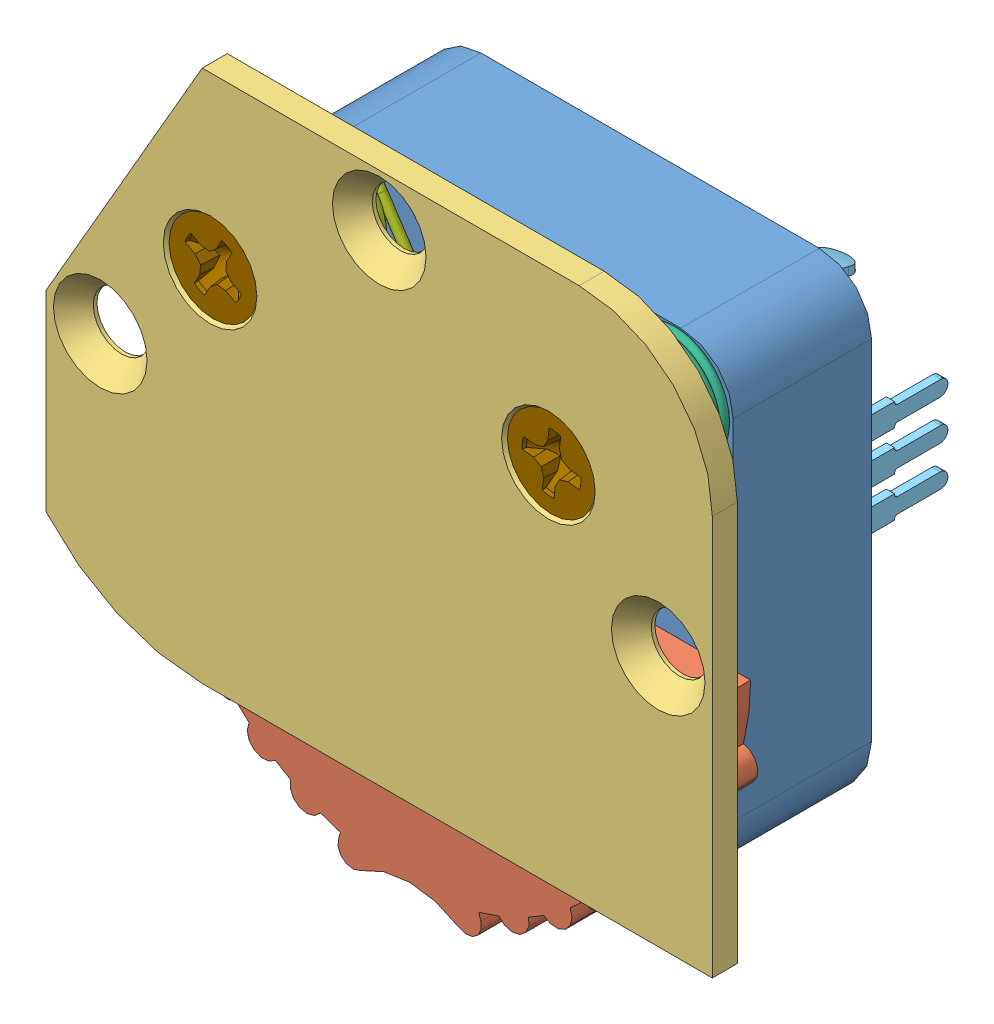
SolidWorks assembly ANT ELEV Switch, configuration Default. Lengths in mm.
Overall size (40.64 39.57 28.62).
13 component instances, 9 part files, 25 mates.
Components (placement in the parent):
- ANT ELEV Mechanism Bracket-1: ANT ELEV Mechanism Bracket [Default] at origin size (27.01 28.27 15)
- ANT ELEV Wheel-1: ANT ELEV Wheel [Default] at (0 0 9.398) x (-1 0 0) z (0 0 -1) size (30.3 23.15 6.22)
- ANT ELEV Mounting Plate-1: ANT ELEV Mounting Plate [Default] at (20.32 -8.9535 9.7282) x (0 1 0) z (0 0 1) size (32.51 40.64 1.52)
- ANT ELEV Pot Clamp-1: ANT ELEV Pot Clamp [Default] at (0 0 -5.2718) x (-1 0 0) z (0 0 -1) size (17.28 9.5 8.47)
- EVU-F2MFK3B14 - Pot, 10k Linear, PTH, M9 x 0.75 bushing, No Switch-1: EVU-F2MFK3B14 - Pot, 10k Linear, PTH, M9 x 0.75 bushing, No Switch [Default] at (0 0 -5.2718) x (0 1 0) z (0 0 1) size (10.82 13.51 27.1)
- 9271K632 - SPRING, TORSION, 360 DEG, LH WOUND, .187 SHAFT x 1.000 LEG, STEEL-1: 9271K632 - SPRING, TORSION, 360 DEG, LH WOUND, .187 SHAFT x 1.000 LEG, STEEL [TRIMMED] at (10.3187 13.1445 8.8392) x (0 0 -1) z (-0.517213 -0.855857 0) size (6.48 7.43 15.72)
- 9271K631 - SPRING, TORSION, 360 DEG, RH WOUND, .187 SHAFT x 1.000 LEG, STEEL-1: 9271K631 - SPRING, TORSION, 360 DEG, RH WOUND, .187 SHAFT x 1.000 LEG, STEEL [TRIMMED] at (-10.3187 13.1445 8.8392) x (0 0 -1) z (0.517213 -0.855857 0) size (6.48 7.43 15.72)
- 93365A120_BRASS HEAT-SET INSERT FOR PLASTICS_4-40-1: 93365A120_BRASS HEAT-SET INSERT FOR PLASTICS_4-40 [93365A120] at (10.3187 13.1445 -4.3828) x (-1 0 0) z (0 -1 0) size (4.37 3.82 4.37)
- 93365A120_BRASS HEAT-SET INSERT FOR PLASTICS_4-40-2: 93365A120_BRASS HEAT-SET INSERT FOR PLASTICS_4-40 [93365A120] at (-10.3187 13.1445 -4.3828) x (-0.987351 0.158553 0) z (-0.158553 -0.987351 0) size (4.37 3.82 4.37)
- 93365A120_BRASS HEAT-SET INSERT FOR PLASTICS_4-40-4: 93365A120_BRASS HEAT-SET INSERT FOR PLASTICS_4-40 [93365A120] at (-9.429 0 1.5875) x (0.959125 0.282984 0) z (0.282984 -0.959125 0) size (4.37 3.82 4.37)
- 90471A427 - FHS, 100DEG, 4-40 X .625, 18-8-1: 90471A427 - FHS, 100DEG, 4-40 X .625, 18-8 [90471A427] at (-10.3187 13.1445 9.8177) x (0.878499 -0.477744 0) z (0 0 1) size (5.38 5.38 15.88)
- 90471A427 - FHS, 100DEG, 4-40 X .625, 18-8-2: 90471A427 - FHS, 100DEG, 4-40 X .625, 18-8 [90471A427] at (10.3187 13.1445 9.8177) x (0.993022 -0.117926 0) z (0 0 1) size (5.38 5.38 15.88)
- 90471A427 - FHS, 100DEG, 4-40 X .625, 18-8-3: 90471A427 - FHS, 100DEG, 4-40 X .625, 18-8 [90471A427] at (-9.429 0 -12.3637) x (-0.184558 0.982822 0) z (0 0 -1) size (5.38 5.38 15.88)
Mates (geometry in assembly coordinates):
- Coincident1: coincident anti-aligned: plane of ANT ELEV Mounting Plate-1 through (0 7.3025 9.7282) normal (0 0 -1); plane of EVU-F2MFK3B14 - Pot, 10k Linear, PTH, M9 x 0.75 bushing, No Switch-1 through (0 0 9.7282) normal (0 0 1)
- Concentric1: concentric aligned: cylinder of ANT ELEV Wheel-1 through (0 0 -1.9625) axis (0 0 1) radius 4.445; cylinder of EVU-F2MFK3B14 - Pot, 10k Linear, PTH, M9 x 0.75 bushing, No Switch-1 through (0 0 -5.2718) axis (0 0 1) radius 3
- Parallel1: parallel aligned: plane of ANT ELEV Mechanism Bracket-1 through (13.5064 -11.938 0) normal (1 0 0); plane of EVU-F2MFK3B14 - Pot, 10k Linear, PTH, M9 x 0.75 bushing, No Switch-1 through (5.75 -4 -5.7708) normal (1 0 0)
- InPlace1: in place: plane of ANT ELEV Mechanism Bracket-1 through (0 0 -5.2718) normal (0 0 -1); plane of ANT ELEV Pot Clamp-1 through (0 0 -5.2718) normal (0 0 -1); moOrthogonalPlaneRef_w of ANT ELEV Mechanism Bracket-1 through (0 0 -5.2718) normal (0 0 -1); plane of ANT ELEV Pot Clamp-1 through (0 0 -5.2718) normal (0 1 0); plane of ANT ELEV Mechanism Bracket-1 through (0 0 -5.2718) normal (0 0 -1); plane of ANT ELEV Pot Clamp-1 through (0 0 -5.2718) normal (-1 0 0); plane of ANT ELEV Mechanism Bracket-1 through (0 0 -5.2718) normal (0 0 -1); unknown of ANT ELEV Pot Clamp-1
- Coincident2: coincident aligned: plane of ANT ELEV Mechanism Bracket-1; plane of ANT ELEV Pot Clamp-1
- Coincident3: coincident aligned: moOrthogonalPlaneRef_w of ANT ELEV Mechanism Bracket-1 through (0 0 -5.2718) normal (0 1 0); plane of ANT ELEV Pot Clamp-1 through (0 0 -5.2718) normal (0 1 0)
- Coincident4: coincident anti-aligned: moOrthogonalPlaneRef_w of ANT ELEV Mechanism Bracket-1 through (0 0 -5.2718) normal (1 0 0); plane of ANT ELEV Pot Clamp-1 through (0 0 -5.2718) normal (-1 0 0)
- Concentric10: concentric anti-aligned: cylinder of ANT ELEV Mechanism Bracket-1 through (10.3187 13.1445 -5.2738) axis (0 0 1) radius 2.3749; line of 9271K632 - SPRING, TORSION, 360 DEG, LH WOUND, .187 SHAFT x 1.000 LEG, STEEL-1 through (10.3187 13.1445 10.1802) axis (0 0 -1)
- Tangent3: tangent: plane of ANT ELEV Wheel-1 through (2.3813 6.7352 3.302) normal (0.866025 -0.5 0); circle of 9271K632 - SPRING, TORSION, 360 DEG, LH WOUND, .187 SHAFT x 1.000 LEG, STEEL-1
- Concentric11: concentric anti-aligned: cylinder of ANT ELEV Mechanism Bracket-1 through (-10.3187 13.1445 -5.2738) axis (0 0 1) radius 2.3749; line of 9271K631 - SPRING, TORSION, 360 DEG, RH WOUND, .187 SHAFT x 1.000 LEG, STEEL-1 through (-10.3187 13.1445 10.1802) axis (0 0 -1)
- Coincident14: coincident aligned: plane of 9271K632 - SPRING, TORSION, 360 DEG, LH WOUND, .187 SHAFT x 1.000 LEG, STEEL-1 through (10.3187 13.1445 8.8392) normal (0 0 -1); plane of 9271K631 - SPRING, TORSION, 360 DEG, RH WOUND, .187 SHAFT x 1.000 LEG, STEEL-1 through (-10.3187 13.1445 8.8392) normal (0 0 -1)
- Tangent5: tangent: plane of ANT ELEV Wheel-1 through (-0.3166 3.1592 3.302) normal (-0.866025 -0.5 0); circle of 9271K631 - SPRING, TORSION, 360 DEG, RH WOUND, .187 SHAFT x 1.000 LEG, STEEL-1
- Distance1: distance = 0.889 mm anti-aligned: plane of 9271K632 - SPRING, TORSION, 360 DEG, LH WOUND, .187 SHAFT x 1.000 LEG, STEEL-1 through (10.3187 13.1445 8.8392) normal (0 0 -1); plane of ANT ELEV Mechanism Bracket-1 through (0 13.1445 9.7282) normal (0 0 1)
- Concentric12: concentric anti-aligned: cone of ANT ELEV Mechanism Bracket-1 through (10.3187 13.1445 -4.3828) axis (0 0 1); cylinder of 93365A120_BRASS HEAT-SET INSERT FOR PLASTICS_4-40-1 through (10.3187 13.1445 -4.3828) axis (0 0 -1) radius 1.9431
- Concentric13: concentric anti-aligned: cone of ANT ELEV Mechanism Bracket-1 through (-10.3187 13.1445 -4.3828) axis (0 0 1); cylinder of 93365A120_BRASS HEAT-SET INSERT FOR PLASTICS_4-40-2 through (-10.3187 13.1445 -4.3828) axis (0 0 -1) radius 1.9431
- Concentric14: concentric anti-aligned: cone of ANT ELEV Mechanism Bracket-1 through (-9.429 0 1.5875) axis (0 0 -1); cylinder of 93365A120_BRASS HEAT-SET INSERT FOR PLASTICS_4-40-4 through (-9.429 0 1.5875) axis (0 0 1) radius 1.9431
- Coincident21: coincident aligned: plane of ANT ELEV Mechanism Bracket-1 through (10.3187 13.1445 -4.3828) normal (0 0 -1); plane of 93365A120_BRASS HEAT-SET INSERT FOR PLASTICS_4-40-1 through (10.3187 13.1445 -4.3828) normal (0 0 -1)
- Coincident22: coincident aligned: plane of ANT ELEV Mechanism Bracket-1 through (-10.3187 13.1445 -4.3828) normal (0 0 -1); plane of 93365A120_BRASS HEAT-SET INSERT FOR PLASTICS_4-40-2 through (-10.3187 13.1445 -4.3828) normal (0 0 -1)
- Coincident23: coincident aligned: plane of ANT ELEV Mechanism Bracket-1 through (-9.429 0 1.5875) normal (0 0 1); plane of 93365A120_BRASS HEAT-SET INSERT FOR PLASTICS_4-40-4 through (-9.429 0 1.5875) normal (0 0 1)
- Concentric15: concentric aligned: cone of ANT ELEV Mounting Plate-1 through (-10.3187 13.1445 10.5473) axis (0 0 -1); cone of 90471A427 - FHS, 100DEG, 4-40 X .625, 18-8-1 through (-10.3187 13.1445 11.0623) axis (0 0 -1)
- Concentric16: concentric aligned: cone of ANT ELEV Mounting Plate-1 through (10.3187 13.1445 10.5473) axis (0 0 -1); cone of 90471A427 - FHS, 100DEG, 4-40 X .625, 18-8-2 through (10.3187 13.1445 11.0623) axis (0 0 -1)
- Concentric17: concentric aligned: cone of ANT ELEV Pot Clamp-1 through (-9.429 0 -13.7468) axis (0 0 1); cone of 90471A427 - FHS, 100DEG, 4-40 X .625, 18-8-3 through (-9.429 0 -13.6083) axis (0 0 1)
- Coincident27: coincident aligned: cone of ANT ELEV Pot Clamp-1 through (-9.429 0 -13.7468) axis (0 0 1); cone of 90471A427 - FHS, 100DEG, 4-40 X .625, 18-8-3 through (-9.429 0 -13.6083) axis (0 0 1)
- Coincident28: coincident: cone of ANT ELEV Mounting Plate-1 through (-10.3187 13.1445 10.5473) axis (0 0 -1); circle of 90471A427 - FHS, 100DEG, 4-40 X .625, 18-8-1
- Coincident29: coincident: cone of ANT ELEV Mounting Plate-1 through (10.3187 13.1445 10.5473) axis (0 0 -1); circle of 90471A427 - FHS, 100DEG, 4-40 X .625, 18-8-2
